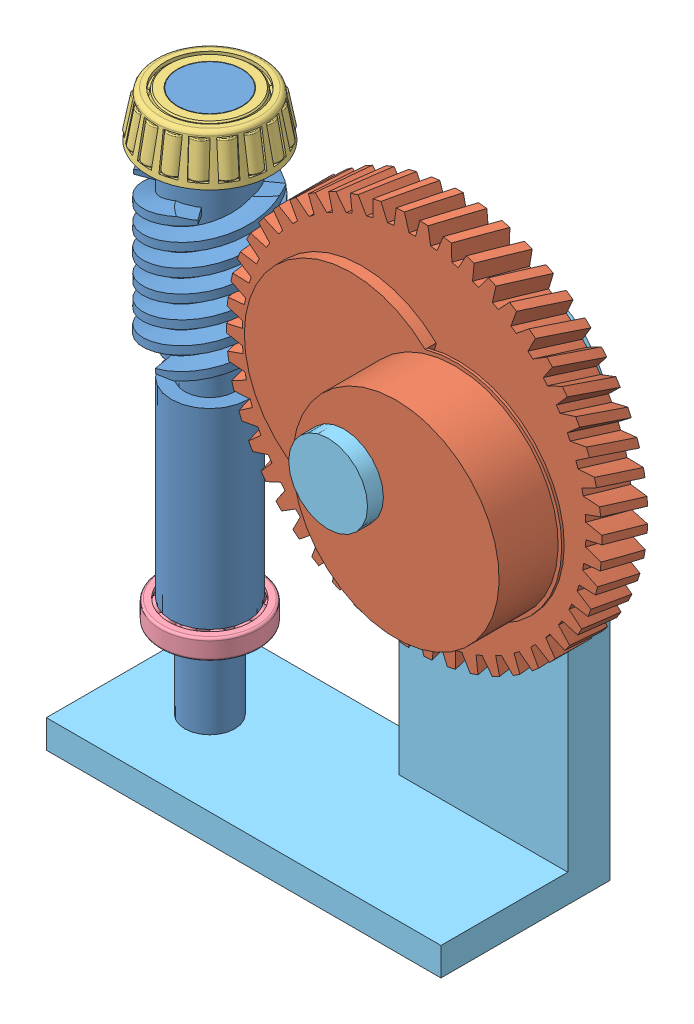
SolidWorks assembly Gears Assembly, configuration Default. Lengths in mm.
Overall size (190.62 222.52 70).
5 component instances, 5 part files, 9 mates.
Components (placement in the parent):
- worm gear-1: worm gear [Default] at (-73.4139 -3.3795 118.0562) x (0 0 1) z (-1 0 0) size (38.77 202.56 38.77)
- Helical Gear-1: Helical Gear [Normal] at (8.555 135.9465 111.2804) x (0.238118 0.971236 0) z (0 0 1) size (133.38 133.38 45.09)
- Cone Bearing-1: Cone Bearing [Default] at (-73.4139 182.2945 118.0562) x (0 1 0) z (0 0 1) size (17.14 43.76 43.71)
- Ball Bearing-1: Ball Bearing [AFBMA 12.2 - 0.6250 - 1.3750 - 0.2812 - 10,DE,NC,10] at (-73.4139 36.2293 118.0562) x (0 1 0) z (0 0 1) size (7.14 34.92 34.92)
- Fixture-1: Fixture [Default] at (-73.4139 -5.9195 118.0562) x (0 0 -1) z (0 -1 0) size (70 140 171.77)
Mates (geometry in assembly coordinates):
- GearMate1: gear = 24.892 : 17.78 mm: cylinder of worm gear-1 through (-73.4139 -3.3795 118.0562) axis (0 -1 0) radius 8.89; cylinder of Helical Gear-1 through (8.555 135.9465 152.4284) axis (0 0 -1) radius 12.446
- Concentric1: concentric aligned: cylinder of worm gear-1 through (-73.4139 -3.3795 118.0562) axis (0 -1 0) radius 13.6525; cylinder of Cone Bearing-1 through (-73.4139 182.2945 118.0562) axis (0 -1 0) radius 11.1125
- Coincident1: coincident aligned: plane of worm gear-1 through (-73.4139 196.6455 129.1687) normal (0 1 0); plane of Cone Bearing-1 through (-91.036 196.6455 118.0562) normal (0 1 0)
- Concentric2: concentric anti-aligned: cylinder of worm gear-1 through (-73.4139 -3.3795 118.0562) axis (0 -1 0) radius 8.89; cylinder of Ball Bearing-1 through (-73.4139 15.5918 118.0562) axis (0 1 0) radius 7.9375
- Coincident2: coincident anti-aligned: plane of worm gear-1 through (-73.4139 39.8005 124.4062) normal (0 -1 0); plane of Ball Bearing-1 through (-82.1388 39.8005 118.0562) normal (0 1 0)
- InPlace1: in place: plane of worm gear-1 through (-73.4139 -5.9195 118.0562) normal (0 -1 0); plane of ? through (0 -5.9195 0) normal (0 -1 0); moOrthogonalPlaneRef_w of worm gear-1 through (-73.4139 -5.9195 118.0562) normal (0 -1 0); unknown of ?; plane of worm gear-1 through (-73.4139 -5.9195 118.0562) normal (0 -1 0); line of ? through (-55 0 -5.9195) axis (0 -1 0); plane of worm gear-1 through (-73.4139 -5.9195 118.0562) normal (0 -1 0); unknown of Fixture-1
- Coincident3: coincident aligned: plane of worm gear-1; plane of Fixture-1
- Coincident4: coincident aligned: moOrthogonalPlaneRef_w of worm gear-1 through (-73.4139 -5.9195 118.0562) normal (1 0 0); plane of Fixture-1
- Coincident5: coincident anti-aligned: moOrthogonalPlaneRef_w of worm gear-1 through (-73.4139 -5.9195 118.0562) normal (0 0 1); plane of Fixture-1
